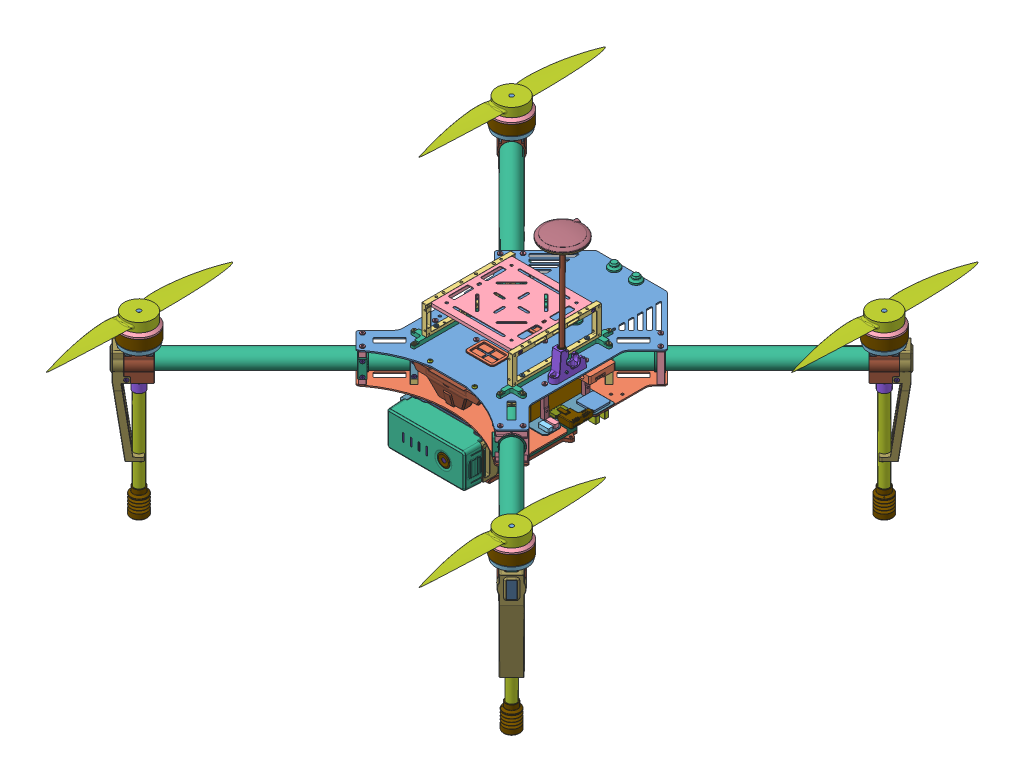
SolidWorks assembly M100_Airframe__CAD, configuration Default. Lengths in mm.
Overall size (567.42 341.74 690.22).
356 component instances, 97 part files, 8 mates.
Components (placement in the parent):
- 100-1: 100 [Default] at origin size (210.39 107.54 255.26)
  - 101-1: 101 [Default] at origin size (210.38 1.5 253.19)
  - 102-1: 102 [Default] at (0 -37 0) x (0 0 1) z (-1 0 0) size (210.39 1.5 210.39)
  - 103-1: 103 [Default] at (57.5962 -17.75 57.5962) x (-0.707107 0 0.707107) z (0.707107 0 0.707107) size (30 35.5 7.06)
  - 104-1: 104 [Default] at (89.5251 -17.75 89.5251) x (-0.707107 0 0.707107) z (0.707107 0 0.707107) size (30 35.5 7)
  - 103-2: 103 [Default] at (-57.5962 -17.75 57.5962) x (0.707107 0 0.707107) z (-0.707107 0 0.707107) size (30 35.5 7.06)
  - 104-2: 104 [Default] at (-94.4749 -17.75 94.4749) x (0.707107 0 0.707107) z (0.707107 0 -0.707107) size (30 35.5 7)
  - 103-3: 103 [Default] at (-57.5962 -17.75 -57.5962) x (0.707107 0 -0.707107) z (-0.707107 0 -0.707107) size (30 35.5 7.06)
  - 104-3: 104 [Default] at (-89.5251 -17.75 -89.5251) x (0.707107 0 -0.707107) z (-0.707107 0 -0.707107) size (30 35.5 7)
  - 103-4: 103 [Default] at (57.5962 -17.75 -57.5962) x (-0.707107 0 -0.707107) z (0.707107 0 -0.707107) size (30 35.5 7.06)
  - 104-4: 104 [Default] at (94.4749 -17.75 -94.4749) x (-0.707107 0 -0.707107) z (-0.707107 0 0.707107) size (30 35.5 7)
  - 105-1: 105 [Default] at (-62.5459 -17.75 -62.5459) x (0 -1 0) z (0.707107 0 0.707107) size (21 6.63 7)
  - 107-1: 107 [Default] at (-50.5 1.5 59.9979) x (0 0 -1) z (0 1 0) size (139.98 19.64 5)
  - 107-2: 107 [Default] at (50.5 1.5 -60.0021) x (0 0 1) z (0 1 0) size (139.98 19.64 5)
  - 107-3: 107 [Default] at (50.5 -37 59.9979) x (0 0 -1) z (0 -1 0) size (139.98 19.64 5)
  - 107-4: 107 [Default] at (-50.5 -37 -60.0021) x (0 0 1) z (0 -1 0) size (139.98 19.64 5)
  - 1080-1: 1080 [Default] at (21.4379 172.8026 -32.3515) x (-1 0 0) z (0 -1 0) size (107.54 107.54 107.54)
    - 1083-1: 1083 [Default] at (-9.315 -53.9231 197.67) x (0.846124 -0.083513 0.526402) z (0.2029 0.963753 -0.173238) size (65.95 81.96 100.76)
      - 1084-1: 1084 [Default] at (14.8112 20.4754 3.2697) x (0.846123 0.49285 0.202916) z (-0.083527 -0.253396 0.96375) size (39 48.7 87.59)
        - 1085-1: 1085 [Default] at (7.4396 73.4003 -13.3971) x (1 0 -0.000017) z (0 -1 0) size (14.5 23.36 14.5)
          - 10850-1: 10850 [Default] at (5.5761 50.8225 94.2464) x (1 0 0) z (0 -1 0) size (14.5 14.5 23.36)
        - 1086-1: 1086 [Default] at (14.5666 -10.4498 39.4253) x (1 0 -0.000017) z (0 -1 0.000177) size (34.91 74.7 29.01)
        - 1087-1: 1087 [Default] at (7.4455 -20.2004 66.9271) x (1 0 -0.000017) z (0.000017 0.000177 1) size (30 30 7)
        - 10880-1: 10880 [Default] at (19.1336 64.3288 17.0227) x (1 0 0) z (0 -1 0) size (39 78.4 26.48)
          - 10881-1: 10881 [Default] at origin size (39 78.4 26.48)
            - 10882-1: 10882 [Default] at origin size (39 78.4 19.9)
            - 10883-1: 10883 [Default] at origin size (39 78.4 9.83)
    - 1082-1: 1082 [Default] at (43.3879 -53.9715 207.3026) x (0 -1 0) z (1 0 0) size (6 34.5 7)
    - 1082-2: 1082 [Default] at (-0.5121 -53.9715 207.3026) x (0 1 0) z (-1 0 0) size (6 34.5 7)
    - 1081-1: 1081 [Default] at (43.3879 -13.3515 207.3026) x (0 -1 0) z (1 0 0) size (6 35.5 5)
  - 1090-1: 1090 [Default] at (-6.5406 -162.4 6.5406) x (1 0 0) z (0 1 0) size (190.05 78.5 35)
    - 1091-1: 1091 [Default] at (6.5406 11.5406 127) size (190 78.5 0.9)
    - 60-1: 60 [Default] at (80.5406 33.7906 111.4) x (0 -1 0) z (0 0 1) size (15.64 8.2 18.6)
    - 60-2: 60 [Default] at (-67.6094 18.2906 143.5) x (-1 0 0) z (0 0 -1) size (15.64 8.2 18.6)
    - CAN-4_1-1: CAN-4_1 [Default] at (78.5906 -7.3844 130.335) x (0 1 0) z (1 0 0) size (19.65 5.87 10.9)
    - CAN-4_1-2: CAN-4_1 [Default] at (-65.5094 1.6156 130.635) x (0 -1 0) z (-1 0 0) size (19.65 5.87 10.9)
    - 30-1: 30 [Default] at (-82.4594 29.0906 127.9) size (10.7 5.7 13.1)
    - 30-2: 30 [Default] at (98.7406 29.0906 127) x (-1 0 0) z (0 0 -1) size (10.7 5.7 13.1)
    - 30-3: 30 [Default] at (98.7406 17.8906 127) x (-1 0 0) z (0 0 -1) size (10.7 5.7 13.1)
    - can-40_1-1: can-40_1 [Default] at (101.5406 -14.8844 126.335) x (0 1 0) z (0 0 1) size (29 24.05 8.55)
    - 1092-1: 1092 [Default] at (6.5406 3.2906 127) x (-1 0 0) z (0 0 -1) size (190 78.5 0.1)
    - BM05B-GHS-TBT_1-1: BM05B-GHS-TBT_1 [Default] at (-69.2602 -22.2344 128.075) x (1 0 0) z (0 -1 0) size (9.5 4.2 4.95)
    - PRODUCT_905935-1: PRODUCT_905935 [Default] at (-68.7094 -30.4844 128.075) x (1 0 0) z (0 -1 0) size (10.75 4.2 4.95)
    - PRODUCT_905935-2: PRODUCT_905935 [Default] at (92.5406 -30.4844 128.075) x (1 0 0) z (0 -1 0) size (10.75 4.2 4.95)
    - BM05B-GHS-TBT_1-2: BM05B-GHS-TBT_1 [Default] at (82.5406 -25.4344 128.075) x (-1 0 0) z (0 1 0) size (9.5 4.2 4.95)
    - 1093-1: 1093 [Default] at (-74.0102 -23.8344 128.85) x (-1 0 0) z (0 0 1) size (11.5 6.25 4.5)
    - 1094-1: 1094 [Default] at (-74.0844 -32.0844 128.85) x (-1 0 0) z (0 0 1) size (12.75 6.25 4.5)
    - 1095-1: 1095 [Default] at (-71.4594 1.6156 130.635) x (0 1 0) z (1 0 0) size (15.65 3.87 6)
    - 1096-1: 1096 [Default] at (-77.3594 31.6906 140.9) x (1 0 0) z (0 0 -1) size (10.2 5.2 8)
    - 1097-1: 1097 [Default] at (-75.4094 20.1906 145.9) x (1 0 0) z (0 0 -1) size (15.6 8.2 10)
    - 1094-2: 1094 [Default] at (87.1656 -32.0844 128.85) x (-1 0 0) z (0 0 1) size (12.75 6.25 4.5)
    - 1093-2: 1093 [Default] at (87.2906 -23.8344 128.85) size (11.5 6.25 4.5)
    - 1096-2: 1096 [Default] at (93.6406 31.6906 114) x (-1 0 0) z (0 0 1) size (10.2 5.2 8)
    - 1096-3: 1096 [Default] at (93.6406 20.4906 114) x (-1 0 0) z (0 0 1) size (10.2 5.2 8)
  - 800-1: 800 [Default] at (59.75 -18.3 41.25) x (1 0 0) z (0 0 -1) size (11.6 32.4 74.01)
  - 800-2: 800 [Default] at (29.75 -18.3 -32.75) x (-1 0 0) z (0 0 1) size (11.6 32.4 74.01)
  - 800-3: 800 [Default] at (-59.75 -18.3 -32.75) x (-1 0 0) z (0 0 1) size (11.6 32.4 74.01)
  - 800-4: 800 [Default] at (-29.75 -18.3 41.25) x (1 0 0) z (0 0 -1) size (11.6 32.4 74.01)
  - 110-1: 110 [Default] at (27 -35.5 -32) x (0 0 -1) z (0 -1 0) size (30 20 3.6)
  - 1081-1: 1081 [Default] at (21.95 -34.5 -19) x (0 0 -1) z (1 0 0) size (6 35.5 5)
  - 1081-2: 1081 [Default] at (-21.95 -34.5 -19) x (0 0 1) z (-1 0 0) size (6 35.5 5)
  - 1081-3: 1081 [Default] at (67.55 -34.5 26.62) x (0 0 1) z (-1 0 0) size (6 35.5 5)
  - 1081-4: 1081 [Default] at (67.55 -34.5 -24) x (0 0 1) z (-1 0 0) size (6 35.5 5)
  - 1081-5: 1081 [Default] at (-67.55 -34.5 -24) x (0 0 -1) z (1 0 0) size (6 35.5 5)
  - 1081-6: 1081 [Default] at (-67.55 -34.5 26.62) x (0 0 -1) z (1 0 0) size (6 35.5 5)
  - 110-2: 110 [Default] at (-39 -35.5 -32) x (0 0 -1) z (0 -1 0) size (30 20 3.6)
  - 111-1: 111 [Default] at (1.1435 -103.0006 83.8197) x (1 0 0) z (0 1 0) size (87.89 38.48 34.04)
    - 1110-1: 1110 [Default] at (-199.0878 14.9697 30.0006) size (87.89 14.06 30.85)
    - 1111-1: 1111 [Default] at (-199.0878 15.5697 30.0006) size (87.89 6.29 29)
    - 1112-1: 1112 [Default] at (14.1225 -16.3739 102.3983) x (0 0 -1) z (0 1 0) size (30.92 41.84 36.53)
      - 11121-1: 11121 [Default] at (12.7706 15.241 27.5) size (24.5 41.84 4.2)
      - 11122-1: 11122 [Default] at (23.2706 15.241 26.75) x (0 1 0) z (0 0 -1) size (9 5 1.2)
      - 11122-2: 11122 [Default] at (18.1706 15.241 26.75) x (0 1 0) z (0 0 -1) size (9 5 1.2)
      - SM04B-GHS-TB-1: SM04B-GHS-TB [Default] at (8.3206 0.841 28.1) x (0 -1 0) z (-1 0 0) size (8.25 4.35 4.85)
      - GHR-04V-S_1-1: GHR-04V-S_1 [Default] at (0.8956 5.5492 30.867) x (0 1 0) z (1 0 0) size (6.25 4.15 5.7)
      - 11123-1: 11123 [Default] at (4.5706 15.241 24.281) x (0 -1 0) z (0 0 1) size (8.21 3.02 9.25)
  - 112-1: 112 [Default] at (-50 -35.4 18) x (0 0 -1) z (0 -1 0) size (24 13.4 2)
  - 112-2: 112 [Default] at (36.6 -35.4 18) x (0 0 -1) z (0 -1 0) size (24 13.4 2)
  - 113-1: 113 [Default] at (-92.9 -35.4 -8.5) x (0 0 -1) z (0 -1 0) size (22 21.4 2.1)
  - 114-1: 114 [Default] at (-15 0 -22) x (1 0 0) z (0 1 0) size (35 25 4)
  - 114-2: 114 [Default] at (-15 0 39) x (1 0 0) z (0 1 0) size (35 25 4)
  - 113-2: 113 [Default] at (92.5 -34.5 -29.9136) x (-1 0 0) z (0 1 0) size (22 21.4 2.1)
  - M2.5-6.7-X-1: M2.5-6.7-X [Default] at (53 -3.5 67.1379) x (1 0 0) z (0 1 0) size (4.45 4.45 9.1)
  - M2.5-6.7-X-2: M2.5-6.7-X [Default] at (67.1421 -3.5 52.9957) x (1 0 0) z (0 1 0) size (4.45 4.45 9.1)
  - M2.5-6.7-X-3: M2.5-6.7-X [Default] at (67.1421 -3.5 -53) x (1 0 0) z (0 1 0) size (4.45 4.45 9.1)
  - M2.5-6.7-X-4: M2.5-6.7-X [Default] at (53 -3.5 -67.1421) x (1 0 0) z (0 1 0) size (4.45 4.45 9.1)
  - M2.5-6.7-X-5: M2.5-6.7-X [Default] at (-67.1421 -3.5 -53) x (1 0 0) z (0 1 0) size (4.45 4.45 9.1)
  - M2.5-6.7-X-6: M2.5-6.7-X [Default] at (-53 -3.5 -67.1421) x (1 0 0) z (0 1 0) size (4.45 4.45 9.1)
  - M2.5-6.7-X-7: M2.5-6.7-X [Default] at (-53 -3.5 67.1379) x (1 0 0) z (0 1 0) size (4.45 4.45 9.1)
  - M2.5-6.7-X-8: M2.5-6.7-X [Default] at (-67.1421 -3.5 52.9957) x (0.950426 0 -0.310952) z (0 1 0) size (4.45 4.45 9.1)
  - M2.5-3.65-D-1: M2.5-3.65-D [Default] at (-84.9289 -3.45 -99.0711) x (1 0 0) z (0 1 0) size (5 5 6.15)
  - M2.5-3.65-D-2: M2.5-3.65-D [Default] at (-99.0711 -3.45 -84.9289) x (1 0 0) z (0 1 0) size (5 5 6.15)
  - M2.5-3.65-D-3: M2.5-3.65-D [Default] at (-99.0711 -3.45 84.9289) x (1 0 0) z (0 1 0) size (5 5 6.15)
  - M2.5-3.65-D-4: M2.5-3.65-D [Default] at (-84.9289 -3.45 99.0711) x (1 0 0) z (0 1 0) size (5 5 6.15)
  - M2.5-3.65-D-5: M2.5-3.65-D [Default] at (-67.55 -3.45 -24) x (1 0 0) z (0 1 0) size (5 5 6.15)
  - M2.5-3.65-D-6: M2.5-3.65-D [Default] at (-67.55 -3.45 26.62) x (1 0 0) z (0 1 0) size (5 5 6.15)
  - M2.5-3.65-D-7: M2.5-3.65-D [Default] at (-21.95 -3.45 21.62) x (1 0 0) z (0 1 0) size (5 5 6.15)
  - M2.5-3.65-D-8: M2.5-3.65-D [Default] at (21.95 -3.45 21.62) x (1 0 0) z (0 1 0) size (5 5 6.15)
  - M2.5-3.65-D-9: M2.5-3.65-D [Default] at (-21.95 -3.45 -19) x (1 0 0) z (0 1 0) size (5 5 6.15)
  - M2.5-3.65-D-10: M2.5-3.65-D [Default] at (67.55 -3.45 -24) x (1 0 0) z (0 1 0) size (5 5 6.15)
  - M2.5-3.65-D-11: M2.5-3.65-D [Default] at (99.0711 -3.45 84.9289) x (1 0 0) z (0 1 0) size (5 5 6.15)
  - M2.5-3.65-D-12: M2.5-3.65-D [Default] at (84.9289 -3.45 99.0711) x (1 0 0) z (0 1 0) size (5 5 6.15)
  - M2.5-3.65-D-13: M2.5-3.65-D [Default] at (99.0711 -3.45 -84.9289) x (0.995978 0 -0.089597) z (0 1 0) size (5 5 6.15)
  - M2.5-3.65-D-14: M2.5-3.65-D [Default] at (84.9289 -3.45 -99.0711) x (1 0 0) z (0 1 0) size (5 5 6.15)
  - M2.5-3.65-D-15: M2.5-3.65-D [Default] at (21.95 -3.45 -19) x (1 0 0) z (0 1 0) size (5 5 6.15)
  - M2.5-3.65-D-16: M2.5-3.65-D [Default] at (67.55 -3.45 26.62) x (1 0 0) z (0 1 0) size (5 5 6.15)
  - M2.5-6.7-X-9: M2.5-6.7-X [Default] at (67.1421 -32 52.9957) x (1 0 0) z (0 -1 0) size (4.45 4.45 9.1)
  - M2.5-6.7-X-10: M2.5-6.7-X [Default] at (53 -32 67.1379) x (1 0 0) z (0 -1 0) size (4.45 4.45 9.1)
  - M2.5-6.7-X-11: M2.5-6.7-X [Default] at (67.1421 -32 -53) x (1 0 0) z (0 -1 0) size (4.45 4.45 9.1)
  - M2.5-6.7-X-12: M2.5-6.7-X [Default] at (53 -32 -67.1421) x (1 0 0) z (0 -1 0) size (4.45 4.45 9.1)
  - M2.5-6.7-X-13: M2.5-6.7-X [Default] at (-67.1421 -32 -53) x (1 0 0) z (0 -1 0) size (4.45 4.45 9.1)
  - M2.5-6.7-X-14: M2.5-6.7-X [Default] at (-53 -32 -67.1421) x (1 0 0) z (0 -1 0) size (4.45 4.45 9.1)
  - M2.5-6.7-X-15: M2.5-6.7-X [Default] at (-67.1421 -32 53) x (1 0 0) z (0 -1 0) size (4.45 4.45 9.1)
  - M2.5-6.7-X-16: M2.5-6.7-X [Default] at (-53 -32 67.1421) x (1 0 0) z (0 -1 0) size (4.45 4.45 9.1)
  - M2.5-3.65-D-17: M2.5-3.65-D [Default] at (84.9289 -32.05 -99.0711) x (1 0 0) z (0 -1 0) size (5 5 6.15)
  - M2.5-3.65-D-18: M2.5-3.65-D [Default] at (99.0711 -32.05 -84.9289) x (0.987922 0 0.154954) z (0 -1 0) size (5 5 6.15)
  - M2.5-3.65-D-19: M2.5-3.65-D [Default] at (21.95 -32.05 -19) x (1 0 0) z (0 -1 0) size (5 5 6.15)
  - M2.5-3.65-D-20: M2.5-3.65-D [Default] at (-21.95 -32.05 -19) x (1 0 0) z (0 -1 0) size (5 5 6.15)
  - M2.5-3.65-D-21: M2.5-3.65-D [Default] at (-21.95 -32.05 21.62) x (1 0 0) z (0 -1 0) size (5 5 6.15)
  - M2.5-3.65-D-22: M2.5-3.65-D [Default] at (21.95 -32.05 21.62) x (1 0 0) z (0 -1 0) size (5 5 6.15)
  - M2.5-3.65-D-23: M2.5-3.65-D [Default] at (67.55 -32.05 26.62) x (1 0 0) z (0 -1 0) size (5 5 6.15)
  - M2.5-3.65-D-24: M2.5-3.65-D [Default] at (67.55 -32.05 -24) x (1 0 0) z (0 -1 0) size (5 5 6.15)
  - M2.5-3.65-D-25: M2.5-3.65-D [Default] at (99.0711 -32.05 84.9289) x (1 0 0) z (0 -1 0) size (5 5 6.15)
  - M2.5-3.65-D-26: M2.5-3.65-D [Default] at (84.9289 -32.05 99.0711) x (1 0 0) z (0 -1 0) size (5 5 6.15)
  - M2.5-3.65-D-27: M2.5-3.65-D [Default] at (-84.9289 -32.05 99.0711) x (1 0 0) z (0 -1 0) size (5 5 6.15)
  - M2.5-3.65-D-28: M2.5-3.65-D [Default] at (-99.0711 -32.05 84.9289) x (1 0 0) z (0 -1 0) size (5 5 6.15)
  - M2.5-3.65-D-29: M2.5-3.65-D [Default] at (-67.55 -32.05 26.62) x (1 0 0) z (0 -1 0) size (5 5 6.15)
  - M2.5-3.65-D-30: M2.5-3.65-D [Default] at (-67.55 -32.05 -24) x (1 0 0) z (0 -1 0) size (5 5 6.15)
  - M2.5-3.65-D-31: M2.5-3.65-D [Default] at (-84.9289 -32.05 -99.0711) x (1 0 0) z (0 -1 0) size (5 5 6.15)
  - M2.5-3.65-D-32: M2.5-3.65-D [Default] at (-99.0711 -32.05 -84.9289) x (1 0 0) z (0 -1 0) size (5 5 6.15)
  - M2-4-╞╗╣√═╖-1: M2-4-╞╗╣√═╖ [Default] at (16.45 -26 21.62) x (0 0 -1) z (1 0 0) size (3.72 3.72 5.3)
  - M2-4-╞╗╣√═╖-2: M2-4-╞╗╣√═╖ [Default] at (16.45 -26 -19) x (0 0 -1) z (1 0 0) size (3.72 3.72 5.3)
  - M2-4-╞╗╣√═╖-3: M2-4-╞╗╣√═╖ [Default] at (-16.45 -26 -19) x (0 -0.642165 0.766566) z (-1 0 0) size (3.72 3.72 5.3)
  - M2-4-╞╗╣√═╖-4: M2-4-╞╗╣√═╖ [Default] at (-14.45 -26 21.62) x (0 -0.127027 0.991899) z (-1 0 0) size (3.72 3.72 5.3)
  - 115-1: 115 [Default] at (-18.5 -5 -60) x (0.310279 0 -0.950646) z (0 1 0) size (15 15 27)
  - 115-2: 115 [Default] at (-13.5 -5 -140) x (1 0 0) z (0 1 0) size (15 15 27)
  - 115-3: 115 [Default] at (13.5 -5 -140) x (0.894558 0 0.446952) z (0 1 0) size (15 15 27)
  - 115-4: 115 [Default] at (18.5 -5 -60) x (1 0 0) z (0 1 0) size (15 15 27)
  - M3-8-╫╘╣Ñ-1: M3-8-╫╘╣Ñ [Default] at (-27.5 -6.5 73) x (1 0 0) z (0 1 0) size (5 5 9.5)
  - M3-8-╫╘╣Ñ-2: M3-8-╫╘╣Ñ [Default] at (27.5 -6.5 73) x (1 0 0) z (0 1 0) size (5 5 9.5)
  - M2.5-5-X-1: M2.5-5-X [Default] at (-53.6364 -9.75 -66.5057) x (-0.707107 0 -0.707107) z (0.707107 0 -0.707107) size (4.45 4.45 7.3)
  - M2.5-5-X-2: M2.5-5-X [Default] at (-53.6364 -25.75 -66.5057) x (-0.645089 -0.409536 -0.645089) z (0.707107 0 -0.707107) size (4.45 4.45 7.3)
  - 105-2: 105 [Default] at (57.5962 -17.75 -57.5962) x (0 -1 0) z (0.707107 0 -0.707107) size (21 6.63 7)
  - 105-3: 105 [Default] at (62.5459 -17.75 62.5459) x (0 -1 0) z (-0.707107 0 -0.707107) size (21 6.63 7)
  - 105-4: 105 [Default] at (-57.5962 -17.75 57.5962) x (0 -1 0) z (-0.707107 0 0.707107) size (21 6.63 7)
  - M2.5-5-X-3: M2.5-5-X [Default] at (53.6364 -9.75 -66.5057) x (-0.071126 0.994928 0.071126) z (-0.707107 0 -0.707107) size (4.45 4.45 7.3)
  - M2.5-5-X-4: M2.5-5-X [Default] at (53.6364 -25.75 -66.5057) x (-0.707107 0 0.707107) z (-0.707107 0 -0.707107) size (4.45 4.45 7.3)
  - M2.5-5-X-5: M2.5-5-X [Default] at (-53.6364 -9.75 66.5057) x (0.707107 0 -0.707107) z (0.707107 0 0.707107) size (4.45 4.45 7.3)
  - M2.5-5-X-6: M2.5-5-X [Default] at (-53.6364 -25.75 66.5057) x (0.707107 0 -0.707107) z (0.707107 0 0.707107) size (4.45 4.45 7.3)
  - M2.5-5-X-7: M2.5-5-X [Default] at (53.6364 -9.75 66.5057) x (0.707107 0 0.707107) z (-0.707107 0 0.707107) size (4.45 4.45 7.3)
  - M2.5-5-X-8: M2.5-5-X [Default] at (53.6364 -25.75 66.5057) x (0.707107 0 0.707107) z (-0.707107 0 0.707107) size (4.45 4.45 7.3)
  - 116-1: 116 [Default] at (0 -11.5 -100) x (1 0 0) z (0 1 0) size (55.98 100 1.6)
- 501-1: 501 [Default] at (0 -87.3 21.8979) x (0 0 -1) z (0 -1 0) size (136.81 112 47.3)
  - 500-1: 500 [Default] at (0 0 -45.3) x (0 -1 0) z (-1 0 0) size (112 4.5 109.3)
  - 502-1: 502 [Default] at origin size (109.3 112 5.5)
  - 503-1: 503 [Default] at (-44.05 33.5 -22.15) x (0 -1 0) z (-1 0 0) size (19.6 45.6 116.2)
    - 5031-1: 5031 [Default] at (-9.4 0 5.7517) x (0 0 -1) z (-1 0 0) size (23.5 45.6 10.7)
    - 5032-1: 5032 [Default] at origin size (10.8 45 98.7)
  - 504-1: 504 [Default] at (0.25 -44.5 -22.15) x (-1 0 0) z (0 -1 0) size (116.2 40.3 10.05)
  - 505-1: 505 [Default] at (5.4433 47.9 -22.15) x (-1 0 0) z (0 1 0) size (97 44.3 5.5)
  - 5060-1: 5060 [Default] at (65.6499 104.2175 1.4118) x (0 0 1) z (0 -1 0) size (44.3 134.81 101.5)
    - 5061-1: 5061 [Default] at (-0.1149 0.0673 -0.0893) size (40.22 134.81 87.01)
      - 5061-1: 5061 [Default] at (-13.3969 69.9326 112.0568) x (0 -1 0) z (0 0 -1) size (118.5 22.62 87)
      - 5062-1: 5062 [Default] at (18.5631 139.7126 109.7693) x (0 0 -1) z (0 1 0) size (66.45 23.95 11.83)
        - 50621-1: 50621 [Default] at origin size (66.45 23.95 11.83)
        - 50622-1: 50622 [Default] at (19.5307 262.3853 -108.7687) x (0.999659 0.026129 0) z (0 0 1) size (15.26 15.26 3.86)
      - 5063-1: 5063 [Default] at (-23.4469 67.7326 112.0568) size (37 106 68)
      - 5064-1: 5064 [Default] at (-22.9816 125.1941 35.0568) x (0 1 0) z (0 0 1) size (18.72 37.2 12.8)
        - 5055-1: 5055 [Default] at (-0.6615 -16.0347 32.8) size (1 37.2 12.8)
        - 5056-1: 5056 [Default] at (-0.6615 -4.4297 34.5) x (0 0 1) z (0 -1 0) size (7.4 18.72 23.81)
      - 507-1: 507 [Default] at (-33.4969 69.9326 112.0568) x (0 -1 0) z (0 0 1) size (118.51 20.13 87.01)
      - 5068-1: 5068 [Default] at (-39.8469 125.7326 68.2568) x (0 -1 0) z (0 0 1) size (1 37.2 66.4)
    - 509-1: 509 [Default] at (-23.4469 117.7326 106.3568) x (0 0 -1) z (0 1 0) size (101.5 44.3 30)
  - M2.5-5-X-1: M2.5-5-X [Default] at (-46.65 -46.5 -37.6) x (-0.923728 -0.383049 0) z (0 0 -1) size (4.45 4.45 7.3)
  - M2.5-5-X-2: M2.5-5-X [Default] at (49.65 -46.5 -37.6) x (-0.923728 -0.383049 0) z (0 0 -1) size (4.45 4.45 7.3)
  - M2.5-5-X-3: M2.5-5-X [Default] at (49.65 31 -37.6) x (-0.923728 -0.383049 0) z (0 0 -1) size (4.45 4.45 7.3)
  - M2.5-5-X-4: M2.5-5-X [Default] at (34.65 31 -37.6) x (-0.923728 -0.383049 0) z (0 0 -1) size (4.45 4.45 7.3)
  - M2.5-5-X-5: M2.5-5-X [Default] at (-49.6567 45.4 -37.6) x (-0.923728 -0.383049 0) z (0 0 -1) size (4.45 4.45 7.3)
  - M2.5-5-X-6: M2.5-5-X [Default] at (49.65 31 -5.7) size (4.45 4.45 7.3)
  - M2.5-5-X-7: M2.5-5-X [Default] at (34.65 31 -5.7) size (4.45 4.45 7.3)
  - M2.5-5-X-8: M2.5-5-X [Default] at (-49.6567 45.4 -5.7) size (4.45 4.45 7.3)
  - M2.5-5-X-9: M2.5-5-X [Default] at (-46.65 -46.5 -5.7) size (4.45 4.45 7.3)
  - M2.5-5-X-10: M2.5-5-X [Default] at (49.65 -46.5 -5.7) size (4.45 4.45 7.3)
  - 510-1: 510 [Default] at (-40.0567 49.4 -22.15) x (1 0 0) z (0 1 0) size (7.2 7.2 10.01)
- 113-1: 113 [Default] at (70 -34.5 -9.1) x (1 0 0) z (0 1 0) size (22 21.4 2.1)
- 600_░▓╫░▓╜╓Φ-1: 600_░▓╫░▓╜╓Φ [Default] at (70 1.5 14.4269) x (0 0 -1) z (0 1 0) size (75.95 107.16 155.06)
  - 601-1: 601 [Default] at (-8.6981 5.5 0) size (39.5 11 32)
  - 602-1: 602 [Default] at (6.423 0 25.4996) x (0.999976 0 -0.006919) z (0.006919 0 0.999976) size (6.5 6.5 27)
  - 603-1: 603 [Default] at (6.3019 5.5 8) x (-0.187052 0 0.98235) z (0 1 0) size (3.5 3.5 13.2)
  - 604-1: 604 [Default] at (6.4092 0 23.4996) x (-0.316284 0.948662 0.002188) z (0.006919 0 0.999976) size (5 5 120)
  - 605-1: 605 [Default] at (45.6816 10.5651 144.064) x (0.965903 0.258819 -0.006683) z (0.006919 0 0.999976) size (52.61 96.85 9.83)
    - 6051-1: 6051 [Default] at (-44.6275 -3.0585 6.6014) size (51.88 50 4.06)
    - 6052-1: 6052 [Default] at (-44.6275 -3.0585 7.1014) size (52.55 96.85 7.7)
  - 606-1: 606 [Default] at (7.2498 0 144.9967) x (0.756788 0.653639 -0.005236) z (-0.006919 0 -0.999976) size (30 30 6.5)
  - 607-1: 607 [Default] at (6.4576 0 30.4995) x (0.999976 0 -0.006919) z (0 -1 0) size (7.8 1.8 7.8)
- 608-1: 608 [Default] at (40.1169 -3.3625 6.0217) x (0 0 -1) z (1 0 0) size (29.88 4 7.99)
  - 6081-1: 6081 [Default] at (-12.5983 2.3625 29.8831) size (29.88 4 7.99)
  - 6082-1: 6082 [Default] at (-12.5983 -0.6375 29.8831) x (1 0 0) z (0 1 0) size (4 4 4)
  - 6082-2: 6082 [Default] at (9.2917 -0.6375 29.8831) x (1 0 0) z (0 1 0) size (4 4 4)
- 200-1: 200 [Default] at (191.0655 14.2101 236.4626) x (-0.707107 0 0.707107) z (-0.707107 0 -0.707107) size (76.27 218.3 281.14)
  - 201-1: 201 [Default] at (-40.748 12.4089 -6.4513) x (-0.923508 0 -0.383579) z (0 -1 0) size (59.06 59.06 40.8)
    - 2010-1: 2010 [Default] at (-1.7887 18.2683 22.2079) x (0.772904 -0.634523 0) z (0 0 1) size (41.96 41.96 12.6)
    - 2011-1: 2011 [Default] at (-1.7887 18.2683 -3.4921) x (0.73008 0.683362 0) z (-0.683362 0.73008 0) size (5 37 5)
    - 2012-1: 2012 [Default] at (-1.7887 18.2683 29.7079) x (-0.894441 0.447185 0) z (0 0 1) size (9 7.93 0.6)
    - 2013-1: 2013 [Default] at (-1.7887 18.2683 25.8079) x (-0.242681 -0.970106 0) z (-0.970106 0.242681 0) size (11 5.01 11)
    - 2013-2: 2013 [Default] at (-1.7887 18.2683 14.1079) x (-0.242681 -0.970106 0) z (-0.970106 0.242681 0) size (11 5.01 11)
    - 2014-1: 2014 [Default] at (-1.7887 18.2683 48.1214) x (0.468584 0.883419 0) z (0 0 1) size (41.96 41.96 7)
    - 2015-1: 2015 [Default] at (-1.7887 18.2683 48.441) x (0.923508 -0.383579 0) z (0 0 1) size (41.62 41.62 22.7)
  - 202-1: 202 [Default] at (-32.0887 -31.899 92.6139) x (-1 0 0) z (0 0 1) size (22 22.01 255.5)
  - 203-1: 203 [Default] at (-32.0887 -183.099 -22.6361) x (-0.141802 0 0.989895) z (0 1 0) size (12 12 130)
  - 204-1: 204 [Default] at (-32.0887 -51.099 -22.6361) x (0 0 1) z (0 -1 0) size (18 18 20)
  - 205-1: 205 [Default] at (-32.1387 -31.899 -42.2361) x (0 -1 0) z (1 0 0) size (18 2 9)
  - 206-1: 206 [Default] at (-32.0887 -31.899 -47.7361) x (0 -1 0) z (-1 0 0) size (23.8 6.5 20.2)
  - 207-1: 207 [Default] at (-32.0887 -31.899 -36.1361) size (26 35.2 27)
  - 208-1: 208 [Default] at (-32.0887 -31.899 -46.1361) size (26 118.02 29.91)
  - 209-1: 209 [Default] at (-32.3181 -92.5632 -35.7787) x (0 -0.991445 0.130526) z (-1 0 0) size (82 5 17.8)
  - M3-5-D-1: M3-5-D [Default] at (-43.5387 -18.899 -32.6361) x (0 0 -1) z (1 0 0) size (5.5 5.5 6.5)
  - M3-5-D-2: M3-5-D [Default] at (-43.5387 -18.899 -12.6361) x (0 0 -1) z (1 0 0) size (5.5 5.5 6.5)
  - M3-5-D-3: M3-5-D [Default] at (-20.6387 -18.899 -32.6361) x (0 0 1) z (-1 0 0) size (5.5 5.5 6.5)
  - M3-5-D-4: M3-5-D [Default] at (-20.6387 -18.899 -12.6361) x (0 0 1) z (-1 0 0) size (5.5 5.5 6.5)
  - 210-1: 210 [Default] at (-32.0887 -31.899 177.7139) x (1 0 0) z (0 0 -1) size (25.5 26 9.6)
  - M2.5-5-X-1: M2.5-5-X [Default] at (-28.2887 -47.399 -33.6361) x (0 0 -1) z (1 0 0) size (4.45 4.45 7.3)
  - M2.5-5-X-2: M2.5-5-X [Default] at (-35.8887 -47.399 -33.6361) x (0 0 1) z (-1 0 0) size (4.45 4.45 7.3)
  - 211-1: 211 [Default] at (-32.0887 -197.899 -22.6361) x (0.899558 0 -0.436802) z (0 1 0) size (12 12 18.5)
  - 212-1: 212 [Default] at (-32.0887 -183.899 -22.6361) x (0.967751 0 0.25191) z (0 1 0) size (12 12 50)
  - 213-1: 213 [Default] at (-32.0887 -199.399 -22.6361) x (0.997967 0 0.063737) z (-0.063737 0 0.997967) size (20 32 20)
- 200-2: 200 [Default] at (-191.1014 14.2101 -236.4649) x (0.707107 0 -0.707107) z (0.707107 0 0.707107) size (76.27 218.3 281.14)
  - 201-1: 201 [Default] at (-40.748 12.4089 -6.4513) x (-0.923508 0 -0.383579) z (0 -1 0) size (59.06 59.06 40.8)
    - 2010-1: 2010 [Default] at (-1.7887 18.2683 22.2079) x (0.772904 -0.634523 0) z (0 0 1) size (41.96 41.96 12.6)
    - 2011-1: 2011 [Default] at (-1.7887 18.2683 -3.4921) x (0.73008 0.683362 0) z (-0.683362 0.73008 0) size (5 37 5)
    - 2012-1: 2012 [Default] at (-1.7887 18.2683 29.7079) x (-0.894441 0.447185 0) z (0 0 1) size (9 7.93 0.6)
    - 2013-1: 2013 [Default] at (-1.7887 18.2683 25.8079) x (-0.242681 -0.970106 0) z (-0.970106 0.242681 0) size (11 5.01 11)
    - 2013-2: 2013 [Default] at (-1.7887 18.2683 14.1079) x (-0.242681 -0.970106 0) z (-0.970106 0.242681 0) size (11 5.01 11)
    - 2014-1: 2014 [Default] at (-1.7887 18.2683 48.1214) x (0.468584 0.883419 0) z (0 0 1) size (41.96 41.96 7)
    - 2015-1: 2015 [Default] at (-1.7887 18.2683 48.441) x (0.923508 -0.383579 0) z (0 0 1) size (41.62 41.62 22.7)
  - 202-1: 202 [Default] at (-32.0887 -31.899 92.6139) x (-1 0 0) z (0 0 1) size (22 22.01 255.5)
  - 203-1: 203 [Default] at (-32.0887 -183.099 -22.6361) x (-0.141802 0 0.989895) z (0 1 0) size (12 12 130)
  - 204-1: 204 [Default] at (-32.0887 -51.099 -22.6361) x (0 0 1) z (0 -1 0) size (18 18 20)
  - 205-1: 205 [Default] at (-32.1387 -31.899 -42.2361) x (0 -1 0) z (1 0 0) size (18 2 9)
  - 206-1: 206 [Default] at (-32.0887 -31.899 -47.7361) x (0 -1 0) z (-1 0 0) size (23.8 6.5 20.2)
  - 207-1: 207 [Default] at (-32.0887 -31.899 -36.1361) size (26 35.2 27)
  - 208-1: 208 [Default] at (-32.0887 -31.899 -46.1361) size (26 118.02 29.91)
  - 209-1: 209 [Default] at (-32.3181 -92.5632 -35.7787) x (0 -0.991445 0.130526) z (-1 0 0) size (82 5 17.8)
  - M3-5-D-1: M3-5-D [Default] at (-43.5387 -18.899 -32.6361) x (0 0 -1) z (1 0 0) size (5.5 5.5 6.5)
  - M3-5-D-2: M3-5-D [Default] at (-43.5387 -18.899 -12.6361) x (0 0 -1) z (1 0 0) size (5.5 5.5 6.5)
  - M3-5-D-3: M3-5-D [Default] at (-20.6387 -18.899 -32.6361) x (0 0 1) z (-1 0 0) size (5.5 5.5 6.5)
  - M3-5-D-4: M3-5-D [Default] at (-20.6387 -18.899 -12.6361) x (0 0 1) z (-1 0 0) size (5.5 5.5 6.5)
  - 210-1: 210 [Default] at (-32.0887 -31.899 177.7139) x (1 0 0) z (0 0 -1) size (25.5 26 9.6)
  - M2.5-5-X-1: M2.5-5-X [Default] at (-28.2887 -47.399 -33.6361) x (0 0 -1) z (1 0 0) size (4.45 4.45 7.3)
  - M2.5-5-X-2: M2.5-5-X [Default] at (-35.8887 -47.399 -33.6361) x (0 0 1) z (-1 0 0) size (4.45 4.45 7.3)
  - 211-1: 211 [Default] at (-32.0887 -197.899 -22.6361) x (0.899558 0 -0.436802) z (0 1 0) size (12 12 18.5)
  - 212-1: 212 [Default] at (-32.0887 -183.899 -22.6361) x (0.967751 0 0.25191) z (0 1 0) size (12 12 50)
  - 213-1: 213 [Default] at (-32.0887 -199.399 -22.6361) x (0.997967 0 0.063737) z (-0.063737 0 0.997967) size (20 32 20)
- 300-1: 300 [Default] at (236.4458 14.2101 -191.0846) x (0.707107 0 0.707107) z (-0.707107 0 0.707107) size (76.27 218.3 281.14)
  - 201-1: 201 [Default] at (-40.748 12.4089 -6.4513) x (-0.923508 0 -0.383579) z (0 -1 0) size (59.06 59.06 40.8)
    - 2010-1: 2010 [Default] at (-1.7887 18.2683 22.2079) x (0.772904 -0.634523 0) z (0 0 1) size (41.96 41.96 12.6)
    - 2011-1: 2011 [Default] at (-1.7887 18.2683 -3.4921) x (0.73008 0.683362 0) z (-0.683362 0.73008 0) size (5 37 5)
    - 2012-1: 2012 [Default] at (-1.7887 18.2683 29.7079) x (-0.894441 0.447185 0) z (0 0 1) size (9 7.93 0.6)
    - 2013-1: 2013 [Default] at (-1.7887 18.2683 25.8079) x (-0.242681 -0.970106 0) z (-0.970106 0.242681 0) size (11 5.01 11)
    - 2013-2: 2013 [Default] at (-1.7887 18.2683 14.1079) x (-0.242681 -0.970106 0) z (-0.970106 0.242681 0) size (11 5.01 11)
    - 2014-1: 2014 [Default] at (-1.7887 18.2683 48.1214) x (0.468584 0.883419 0) z (0 0 1) size (41.96 41.96 7)
    - 2015-1: 2015 [Default] at (-1.7887 18.2683 48.441) x (0.923508 -0.383579 0) z (0 0 1) size (41.62 41.62 22.7)
  - 202-1: 202 [Default] at (-32.0887 -31.899 92.6139) x (-1 0 0) z (0 0 1) size (22 22.01 255.5)
  - 203-1: 203 [Default] at (-32.0887 -183.099 -22.6361) x (-0.141802 0 0.989895) z (0 1 0) size (12 12 130)
  - 204-1: 204 [Default] at (-32.0887 -51.099 -22.6361) x (0 0 1) z (0 -1 0) size (18 18 20)
  - 205-1: 205 [Default] at (-32.1387 -31.899 -42.2361) x (0 -1 0) z (1 0 0) size (18 2 9)
  - 206-1: 206 [Default] at (-32.0887 -31.899 -47.7361) x (0 -1 0) z (-1 0 0) size (23.8 6.5 20.2)
  - 207-1: 207 [Default] at (-32.0887 -31.899 -36.1361) size (26 35.2 27)
  - 208-1: 208 [Default] at (-32.0887 -31.899 -46.1361) size (26 118.02 29.91)
  - 209-1: 209 [Default] at (-32.3181 -92.5632 -35.7787) x (0 -0.991445 0.130526) z (-1 0 0) size (82 5 17.8)
  - M3-5-D-1: M3-5-D [Default] at (-43.5387 -18.899 -32.6361) x (0 0 -1) z (1 0 0) size (5.5 5.5 6.5)
  - M3-5-D-2: M3-5-D [Default] at (-43.5387 -18.899 -12.6361) x (0 0 -1) z (1 0 0) size (5.5 5.5 6.5)
  - M3-5-D-3: M3-5-D [Default] at (-20.6387 -18.899 -32.6361) x (0 0 1) z (-1 0 0) size (5.5 5.5 6.5)
  - M3-5-D-4: M3-5-D [Default] at (-20.6387 -18.899 -12.6361) x (0 0 1) z (-1 0 0) size (5.5 5.5 6.5)
  - 210-1: 210 [Default] at (-32.0887 -31.899 177.7139) x (-1 0 0) z (0 0 -1) size (25.5 26 9.6)
  - M2.5-5-X-1: M2.5-5-X [Default] at (-28.2887 -47.399 -33.6361) x (0 0 -1) z (1 0 0) size (4.45 4.45 7.3)
  - M2.5-5-X-2: M2.5-5-X [Default] at (-35.8887 -47.399 -33.6361) x (0 0 1) z (-1 0 0) size (4.45 4.45 7.3)
  - 301-1: 301 [Default] at (-32.0887 -44.349 -22.6361) size (11.2 1.5 11.2)
  - 212-1: 212 [Default] at (-32.0887 -183.899 -22.6361) x (0.22627 0 -0.974065) z (0 1 0) size (12 12 50)
  - 213-1: 213 [Default] at (-32.0887 -199.399 -22.6361) size (20 32 20)
  - 211-1: 211 [Default] at (-32.0887 -197.899 -22.6361) x (0.518822 0 -0.854882) z (0 1 0) size (12 12 18.5)
- 300-2: 300 [Default] at (-236.4817 14.2101 191.0823) x (-0.707107 0 -0.707107) z (0.707107 0 -0.707107) size (76.27 218.3 281.14)
  - 201-1: 201 [Default] at (-40.748 12.4089 -6.4513) x (-0.923508 0 -0.383579) z (0 -1 0) size (59.06 59.06 40.8)
    - 2010-1: 2010 [Default] at (-1.7887 18.2683 22.2079) x (0.772904 -0.634523 0) z (0 0 1) size (41.96 41.96 12.6)
    - 2011-1: 2011 [Default] at (-1.7887 18.2683 -3.4921) x (0.73008 0.683362 0) z (-0.683362 0.73008 0) size (5 37 5)
    - 2012-1: 2012 [Default] at (-1.7887 18.2683 29.7079) x (-0.894441 0.447185 0) z (0 0 1) size (9 7.93 0.6)
    - 2013-1: 2013 [Default] at (-1.7887 18.2683 25.8079) x (-0.242681 -0.970106 0) z (-0.970106 0.242681 0) size (11 5.01 11)
    - 2013-2: 2013 [Default] at (-1.7887 18.2683 14.1079) x (-0.242681 -0.970106 0) z (-0.970106 0.242681 0) size (11 5.01 11)
    - 2014-1: 2014 [Default] at (-1.7887 18.2683 48.1214) x (0.468584 0.883419 0) z (0 0 1) size (41.96 41.96 7)
    - 2015-1: 2015 [Default] at (-1.7887 18.2683 48.441) x (0.923508 -0.383579 0) z (0 0 1) size (41.62 41.62 22.7)
  - 202-1: 202 [Default] at (-32.0887 -31.899 92.6139) x (-1 0 0) z (0 0 1) size (22 22.01 255.5)
  - 203-1: 203 [Default] at (-32.0887 -183.099 -22.6361) x (-0.141802 0 0.989895) z (0 1 0) size (12 12 130)
  - 204-1: 204 [Default] at (-32.0887 -51.099 -22.6361) x (0 0 1) z (0 -1 0) size (18 18 20)
  - 205-1: 205 [Default] at (-32.1387 -31.899 -42.2361) x (0 -1 0) z (1 0 0) size (18 2 9)
  - 206-1: 206 [Default] at (-32.0887 -31.899 -47.7361) x (0 -1 0) z (-1 0 0) size (23.8 6.5 20.2)
  - 207-1: 207 [Default] at (-32.0887 -31.899 -36.1361) size (26 35.2 27)
  - 208-1: 208 [Default] at (-32.0887 -31.899 -46.1361) size (26 118.02 29.91)
  - 209-1: 209 [Default] at (-32.3181 -92.5632 -35.7787) x (0 -0.991445 0.130526) z (-1 0 0) size (82 5 17.8)
  - M3-5-D-1: M3-5-D [Default] at (-43.5387 -18.899 -32.6361) x (0 0 -1) z (1 0 0) size (5.5 5.5 6.5)
  - M3-5-D-2: M3-5-D [Default] at (-43.5387 -18.899 -12.6361) x (0 0 -1) z (1 0 0) size (5.5 5.5 6.5)
  - M3-5-D-3: M3-5-D [Default] at (-20.6387 -18.899 -32.6361) x (0 0 1) z (-1 0 0) size (5.5 5.5 6.5)
  - M3-5-D-4: M3-5-D [Default] at (-20.6387 -18.899 -12.6361) x (0 0 1) z (-1 0 0) size (5.5 5.5 6.5)
  - 210-1: 210 [Default] at (-32.0887 -31.899 177.7139) x (-1 0 0) z (0 0 -1) size (25.5 26 9.6)
  - M2.5-5-X-1: M2.5-5-X [Default] at (-28.2887 -47.399 -33.6361) x (0 0 -1) z (1 0 0) size (4.45 4.45 7.3)
  - M2.5-5-X-2: M2.5-5-X [Default] at (-35.8887 -47.399 -33.6361) x (0 0 1) z (-1 0 0) size (4.45 4.45 7.3)
  - 301-1: 301 [Default] at (-32.0887 -44.349 -22.6361) size (11.2 1.5 11.2)
  - 212-1: 212 [Default] at (-32.0887 -183.899 -22.6361) x (0.22627 0 -0.974065) z (0 1 0) size (12 12 50)
  - 213-1: 213 [Default] at (-32.0887 -199.399 -22.6361) size (20 32 20)
  - 211-1: 211 [Default] at (-32.0887 -197.899 -22.6361) x (0.518822 0 -0.854882) z (0 1 0) size (12 12 18.5)
- M2.5-6.7-X-1: M2.5-6.7-X [Default] at (70 -2.5 18.62) x (1 0 0) z (0 1 0) size (4.45 4.45 9.1)
- M2.5-6.7-X-2: M2.5-6.7-X [Default] at (53 -4.5 9.1079) x (0.745693 0 0.66629) z (0 1 0) size (4.45 4.45 9.1)
- 700-1: 700 [Default] at (78.0168 27.65 -30.3456) x (0 0 1) z (0 -1 0) size (32 16 8.7)
  - 701-1: 701 [Default] at (-12.0864 -8.0332 27.65) size (32 16 8.7)
- 401-1: 401 [Default] at (60 -2.3503 74.3244) x (0 0 1) z (-1 0 0) size (110 35.6 112.4)
  - 402-1: 402 [Default] at (-74.3265 26.3503 110) size (110 35 6.2)
  - 402-2: 402 [Default] at (-74.3265 26.3503 10) x (-1 0 0) z (0 0 -1) size (110 35 6.2)
  - 403-1: 403 [Default] at (-124.3265 43.8503 9) x (1 0 0) z (0 -1 0) size (100 102 4)
  - M2.5-5-X-1: M2.5-5-X [Default] at (-119.3265 41.3503 11.5) x (-0.581498 0.813548 0) z (0 0 -1) size (4.45 4.45 7.3)
  - M2.5-5-X-2: M2.5-5-X [Default] at (-119.3265 41.3503 108.5) size (4.45 4.45 7.3)
  - M2.5-5-X-3: M2.5-5-X [Default] at (-29.3265 41.3503 108.5) x (0.883354 0.468706 0) z (0 0 1) size (4.45 4.45 7.3)
  - M2.5-5-X-4: M2.5-5-X [Default] at (-29.3265 41.3503 11.5) x (-0.854804 -0.518951 0) z (0 0 -1) size (4.45 4.45 7.3)
- M3-5-X-1: M3-5-X [Default] at (-53 4.7 -40.0021) x (1 0 0) z (0 1 0) size (4.5 4.5 6.5)
- M3-5-X-2: M3-5-X [Default] at (-53 4.7 39.9979) x (0.958824 0 -0.283999) z (0 1 0) size (4.5 4.5 6.5)
- M3-5-X-3: M3-5-X [Default] at (53 4.7 39.9979) x (1 0 0) z (0 1 0) size (4.5 4.5 6.5)
- M3-5-X-4: M3-5-X [Default] at (53 4.7 -40.0021) x (0.559367 0 0.82892) z (0 1 0) size (4.5 4.5 6.5)
- 106-1: 106 [Default] at (88.712 -17.75 89.4191) x (0 1 0) z (0.707107 0 0.707107) size (22 5.7 8.3)
- M2.5-5-X-1: M2.5-5-X [Default] at (85.2118 -9.25 98.7882) x (0.707107 0 0.707107) z (-0.707107 0 0.707107) size (4.45 4.45 7.3)
- M2.5-5-X-2: M2.5-5-X [Default] at (85.2118 -26.25 98.7882) x (0.707107 0 0.707107) z (-0.707107 0 0.707107) size (4.45 4.45 7.3)
- 106-2: 106 [Default] at (-94.5809 -17.75 95.288) x (0 1 0) z (0.707107 0 -0.707107) size (22 5.7 8.3)
- M2.5-5-X-3: M2.5-5-X [Default] at (-85.2118 -9.25 98.7882) x (0.707107 0 -0.707107) z (0.707107 0 0.707107) size (4.45 4.45 7.3)
- M2.5-5-X-4: M2.5-5-X [Default] at (-85.2118 -26.25 98.7882) x (0.707107 0 -0.707107) z (0.707107 0 0.707107) size (4.45 4.45 7.3)
- M2.5-5-X-5: M2.5-5-X [Default] at (-85.2118 -9.25 -98.7882) x (-0.707107 0 -0.707107) z (0.707107 0 -0.707107) size (4.45 4.45 7.3)
- 106-3: 106 [Default] at (-94.5809 -17.75 -95.288) x (0 -1 0) z (0.707107 0 0.707107) size (22 5.7 8.3)
- M2.5-5-X-6: M2.5-5-X [Default] at (-85.2118 -26.25 -98.7882) x (-0.707107 0 -0.707107) z (0.707107 0 -0.707107) size (4.45 4.45 7.3)
- 106-4: 106 [Default] at (88.712 -17.75 -89.4191) x (0 -1 0) z (0.707107 0 -0.707107) size (22 5.7 8.3)
- M2.5-5-X-7: M2.5-5-X [Default] at (85.2118 -26.25 -98.7882) x (-0.071126 0.994928 0.071126) z (-0.707107 0 -0.707107) size (4.45 4.45 7.3)
- M2.5-5-X-8: M2.5-5-X [Default] at (85.2118 -9.25 -98.7882) x (-0.071126 0.994928 0.071126) z (-0.707107 0 -0.707107) size (4.45 4.45 7.3)
- M2.5-5-X-9: M2.5-5-X [Default] at (-53 -37.6 -30.0021) x (1 0 0) z (0 -1 0) size (4.45 4.45 7.3)
- M2.5-5-X-10: M2.5-5-X [Default] at (-53 -37.6 49.9979) x (1 0 0) z (0 -1 0) size (4.45 4.45 7.3)
- M2.5-5-X-11: M2.5-5-X [Default] at (53 -37.6 -30.0021) x (1 0 0) z (0 -1 0) size (4.45 4.45 7.3)
- M2.5-5-X-12: M2.5-5-X [Default] at (53 -37.6 49.9979) x (1 0 0) z (0 -1 0) size (4.45 4.45 7.3)
- 600_░▓╫░▓╜╓Φ-2: 600_░▓╫░▓╜╓Φ [Default] at (70 1.5 14.4269) x (0 0 -1) z (0 1 0) size (75.95 107.16 155.06)
  - 601-1: 601 [Default] at (-8.6981 5.5 0) size (39.5 11 32)
  - 602-1: 602 [Default] at (6.423 0 25.4996) x (0.999976 0 -0.006919) z (0.006919 0 0.999976) size (6.5 6.5 27)
  - 603-1: 603 [Default] at (6.3019 5.5 8) x (-0.187052 0 0.98235) z (0 1 0) size (3.5 3.5 13.2)
  - 604-1: 604 [Default] at (6.4092 0 23.4996) x (-0.316284 0.948662 0.002188) z (0.006919 0 0.999976) size (5 5 120)
  - 605-1: 605 [Default] at (45.6816 10.5651 144.064) x (0.965903 0.258819 -0.006683) z (0.006919 0 0.999976) size (52.61 96.85 9.83)
    - 6051-1: 6051 [Default] at (-44.6275 -3.0585 6.6014) size (51.88 50 4.06)
    - 6052-1: 6052 [Default] at (-44.6275 -3.0585 7.1014) size (52.55 96.85 7.7)
  - 606-1: 606 [Default] at (7.2498 0 144.9967) x (0.756788 0.653639 -0.005236) z (-0.006919 0 -0.999976) size (30 30 6.5)
  - 607-1: 607 [Default] at (6.4576 0 30.4995) x (0.999976 0 -0.006919) z (0 -1 0) size (7.8 1.8 7.8)
- M2.5-6.7-X-3: M2.5-6.7-X [Default] at (70 -4.5 -3.27) x (1 0 0) z (0 1 0) size (4.45 4.45 9.1)
- prop-1: prop [Default] at (231.7905 27.8108 -218.4954) x (1 0.00044 0) z (0 -0.000021 1) size (36.07 11.06 230.66)
- prop-2: prop [Default] at (-227.769 27.8108 -218.4954) x (1 0.00044 0) z (0 -0.000021 1) size (36.07 11.06 230.66)
- prop-3: prop [Default] at (-227.769 27.8108 241.0641) x (1 0.00044 0) z (0 -0.000021 1) size (36.07 11.06 230.66)
- prop-4: prop [Default] at (231.7905 27.8108 241.0641) x (1 0.00044 0) z (0 -0.000021 1) size (36.07 11.06 230.66)
Mates (geometry in assembly coordinates):
- Concentric1: concentric: cylinder of 300-1/201-1/2011-1 through (229.7618 75.3989 -229.7809) axis (0 1 0) radius 2.5; cylinder of prop-1 through (229.7618 33.0601 -229.7809) axis (0 -1 0) radius 2.54
- Coincident1: coincident: plane of 300-1/201-1/2014-1 through (231.3558 22.0111 -231.7068) normal (0 1 0); plane of prop-1 through (229.7618 22.0111 -229.7809) normal (0 -1 0)
- Concentric2: concentric: cylinder of 200-2/201-1/2011-1 through (-229.7977 75.3989 -229.7809) axis (0 1 0) radius 2.5; cylinder of prop-2 through (-229.7977 33.0601 -229.7809) axis (0 -1 0) radius 2.54
- Coincident2: coincident: plane of 200-2/201-1/2014-1 through (-231.7236 22.0111 -231.3749) normal (0 1 0); plane of prop-2 through (-229.7977 22.0111 -229.7809) normal (0 -1 0)
- Concentric3: concentric: cylinder of 300-2/201-1/2011-1 through (-229.7977 75.3989 229.7786) axis (0 1 0) radius 2.5; cylinder of prop-3 through (-229.7977 33.0601 229.7786) axis (0 -1 0) radius 2.54
- Coincident3: coincident: plane of 300-2/201-1/2014-1 through (-231.3917 22.0111 231.7045) normal (0 1 0); plane of prop-3 through (-229.7977 22.0111 229.7786) normal (0 -1 0)
- Concentric4: concentric: cylinder of 200-1/201-1/2011-1 through (229.7618 75.3989 229.7786) axis (0 1 0) radius 2.5; cylinder of prop-4 through (229.7618 33.0601 229.7786) axis (0 -1 0) radius 2.54
- Coincident4: coincident: plane of 200-1/201-1/2014-1 through (231.6877 22.0111 231.3726) normal (0 1 0); plane of prop-4 through (229.7618 22.0111 229.7786) normal (0 -1 0)
